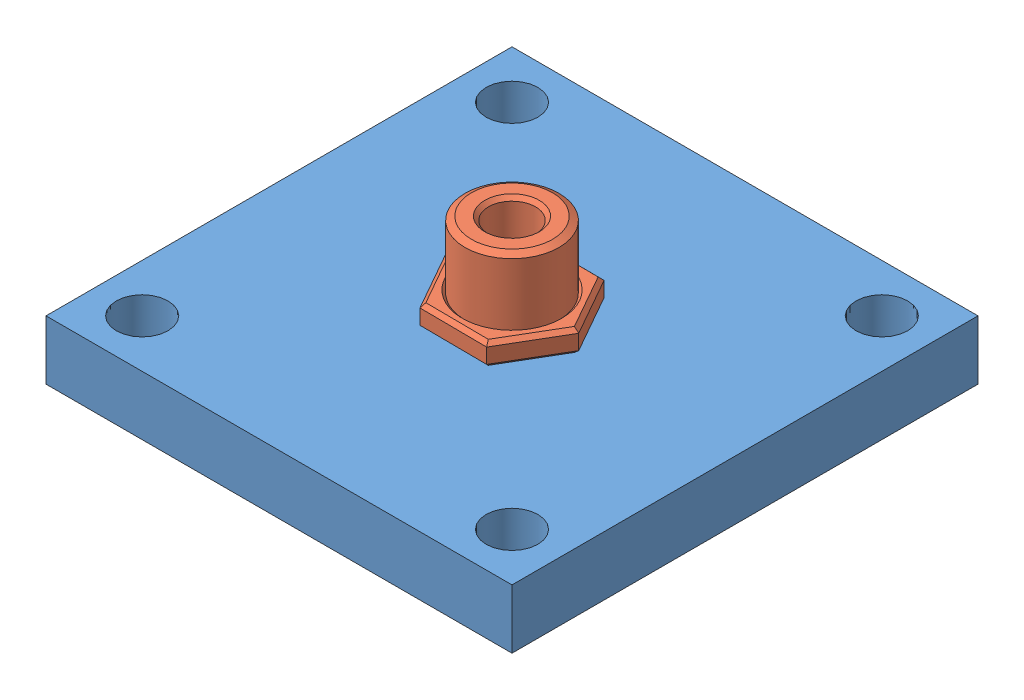
SolidWorks assembly SMA mount, configuration Default. Lengths in mm.
Overall size (31.5 9.84 31.5).
2 component instances, 2 part files, 4 mates.
Components (placement in the parent):
- SMA mount-1: SMA mount [Default] at (16.6392 12.6961 22.787) size (31.5 4 31.5)
- HASMA-Solidworks-1: HASMA-Solidworks [Default] at (16.6392 12.8861 22.787) x (0.999968 0 0.007988) z (0 1 0) size (9.09 7.87 9.65)
Mates (geometry in assembly coordinates):
- Concentric1: concentric: circle of SMA mount-1; circle of HAFC-Solidworks-1
- Coincident1: coincident anti-aligned: plane of SMA mount-1 through (16.6392 16.6961 22.787) normal (0 1 0); plane of HAFC-Solidworks-1 through (14.3817 16.6961 26.2424) normal (0 -1 0)
- Concentric2: concentric anti-aligned: cylinder of SMA mount-1 through (16.6392 16.6961 22.787) axis (0 1 0) radius 2.7051; cylinder of HASMA-Solidworks-1 through (16.6392 22.5381 22.787) axis (0 -1 0) radius 3.175
- Coincident2: coincident anti-aligned: plane of SMA mount-1 through (16.6392 16.6961 22.787) normal (0 1 0); plane of HASMA-Solidworks-1 through (12.0933 16.6961 22.7507) normal (0 -1 0)
